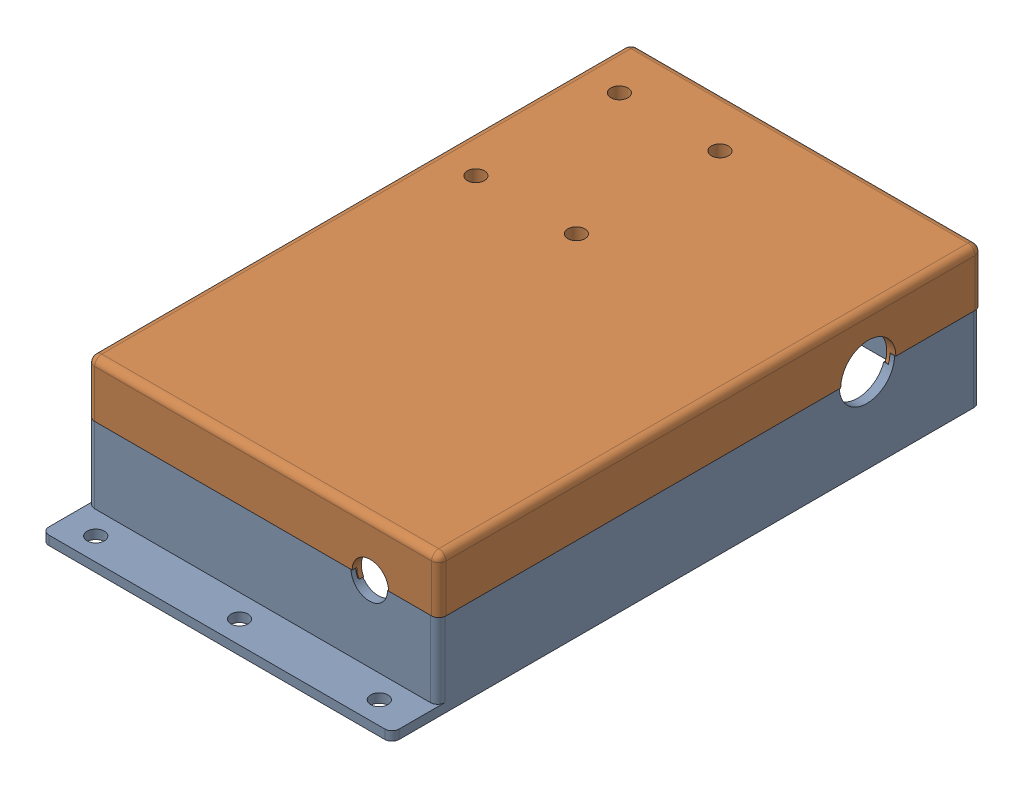
SolidWorks assembly Motor Covor, configuration Default. Lengths in mm.
Overall size (97.88 38.86 164.14).
2 component instances, 2 part files, 3 mates.
Components (placement in the parent):
- Chain driven motor cover 006 923-1: Chain driven motor cover 006 923 [Default] at (25.4602 34.7872 64.3473) size (97.57 23.62 164.07)
- Chain driven motor cover 006 lid 923 (3)-1: Chain driven motor cover 006 lid 923 (3) [Default] at (25.6158 72.3762 64.3127) x (1 0 0) z (0 0 -1) size (97.88 17.78 151.41)
Mates (geometry in assembly coordinates):
- Coincident2: coincident aligned: plane of Chain driven motor cover 006 923-1 through (-23.3253 58.4062 140.0201) normal (0 0 1); plane of Chain driven motor cover 006 lid 923 (3)-1 through (25.6158 71.1062 140.0201) normal (0 0 1)
- Coincident3: coincident aligned: plane of Chain driven motor cover 006 923-1 through (-23.3253 58.4062 -11.3255) normal (-1 0 0); plane of Chain driven motor cover 006 lid 923 (3)-1 through (-23.3253 71.1062 64.3127) normal (-1 0 0)
- Coincident6: coincident anti-aligned: plane of Chain driven motor cover 006 923-1 through (-19.7853 55.8662 136.4801) normal (0 1 0); plane of Chain driven motor cover 006 lid 923 (3)-1 through (71.0169 55.8662 -7.8547) normal (0 -1 0)
